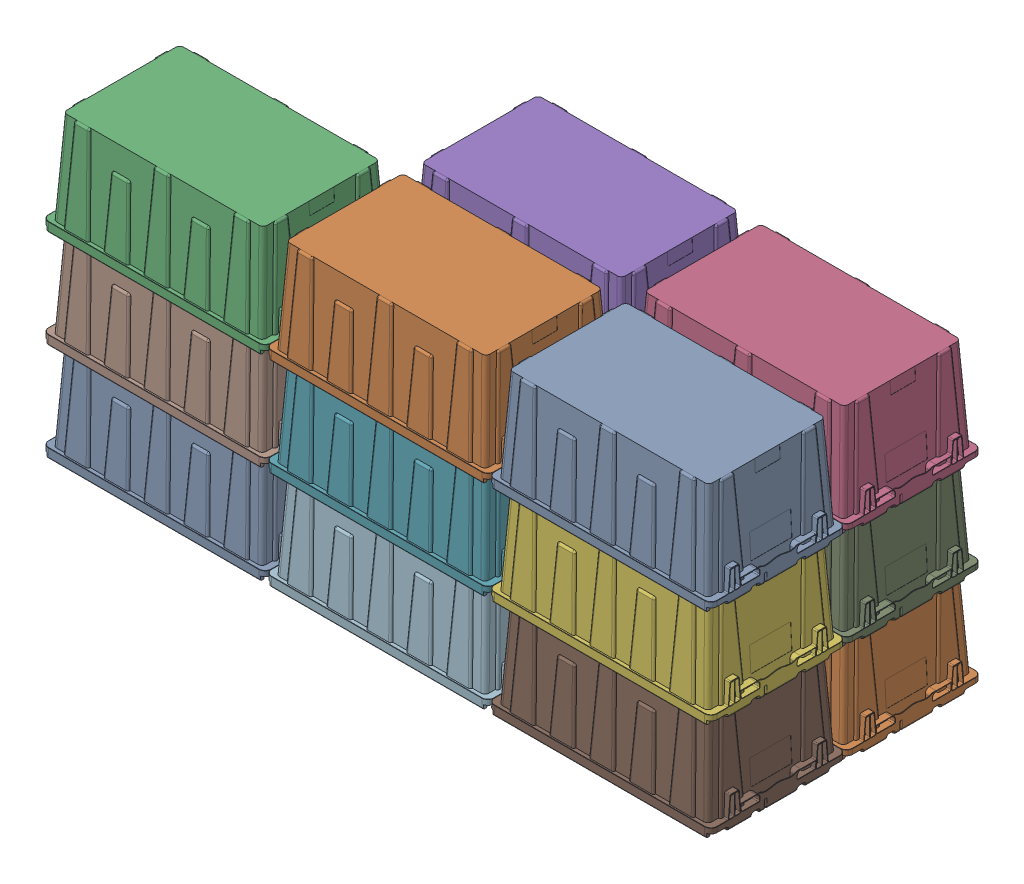
SolidWorks assembly ALLIANCE_STATION_GP1_ASM, configuration Default. Lengths in mm.
Overall size (2051.05 910.73 825.5).
15 component instances, 1 part files, 0 mates.
Components (placement in the parent):
- GRAY_TOTE-1: GRAY_TOTE [Default] at (339.725 0 0) x (0 -1 0) z (-1 0 0) size (313.83 412.75 692.15)
- GRAY_TOTE-2: GRAY_TOTE [Default] at (-339.725 0 0) x (0 -1 0) z (-1 0 0) size (313.83 412.75 692.15)
- GRAY_TOTE-3: GRAY_TOTE [Default] at (-1019.175 0 0) x (0 -1 0) z (-1 0 0) size (313.83 412.75 692.15)
- GRAY_TOTE-4: GRAY_TOTE [Default] at (339.725 0 -412.75) x (0 -1 0) z (-1 0 0) size (313.83 412.75 692.15)
- GRAY_TOTE-5: GRAY_TOTE [Default] at (-339.725 0 -412.75) x (0 -1 0) z (-1 0 0) size (313.83 412.75 692.15)
- GRAY_TOTE-6: GRAY_TOTE [Default] at (339.725 -298.45 0) x (0 -1 0) z (-1 0 0) size (313.83 412.75 692.15)
- GRAY_TOTE-7: GRAY_TOTE [Default] at (-339.725 -298.45 0) x (0 -1 0) z (-1 0 0) size (313.83 412.75 692.15)
- GRAY_TOTE-8: GRAY_TOTE [Default] at (-1019.175 -298.45 0) x (0 -1 0) z (-1 0 0) size (313.83 412.75 692.15)
- GRAY_TOTE-9: GRAY_TOTE [Default] at (339.725 -298.45 -412.75) x (0 -1 0) z (-1 0 0) size (313.83 412.75 692.15)
- GRAY_TOTE-10: GRAY_TOTE [Default] at (-339.725 -298.45 -412.75) x (0 -1 0) z (-1 0 0) size (313.83 412.75 692.15)
- GRAY_TOTE-11: GRAY_TOTE [Default] at (339.725 -596.9 0) x (0 -1 0) z (-1 0 0) size (313.83 412.75 692.15)
- GRAY_TOTE-12: GRAY_TOTE [Default] at (-339.725 -596.9 0) x (0 -1 0) z (-1 0 0) size (313.83 412.75 692.15)
- GRAY_TOTE-13: GRAY_TOTE [Default] at (-1019.175 -596.9 0) x (0 -1 0) z (-1 0 0) size (313.83 412.75 692.15)
- GRAY_TOTE-14: GRAY_TOTE [Default] at (339.725 -596.9 -412.75) x (0 -1 0) z (-1 0 0) size (313.83 412.75 692.15)
- GRAY_TOTE-15: GRAY_TOTE [Default] at (-339.725 -596.9 -412.75) x (0 -1 0) z (-1 0 0) size (313.83 412.75 692.15)
